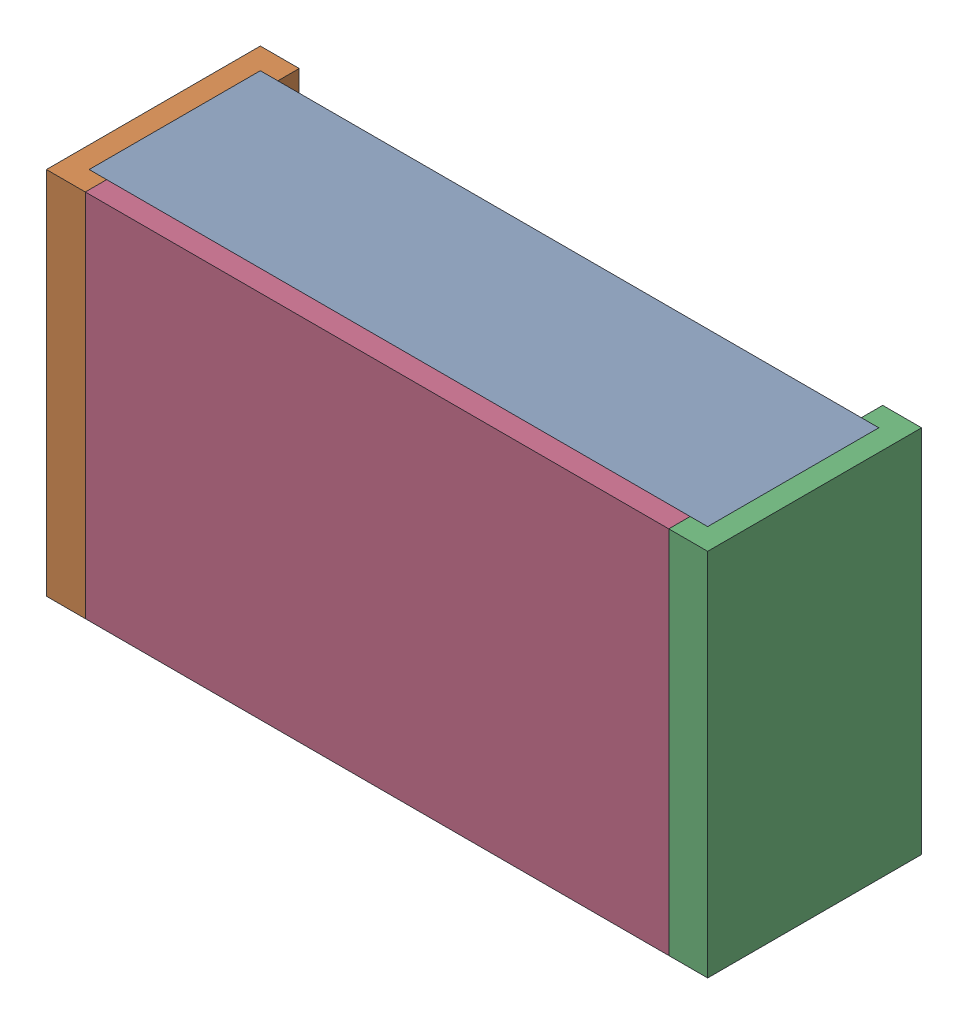
SolidWorks assembly 7434017360, configuration Default. Lengths in mm.
Overall size (1.7 0.95 0.55).
6 component instances, 3 part files, 0 mates.
Components (placement in the parent):
- Mid_Body-1: Mid_Body [Default] at (-0.85 -0.475 0) size (1.59 0.95 0.44)
- Terminal-1: Terminal [Default] at (-0.85 -0.475 0) size (0.1 0.95 0.55)
  - Open_CASCADE_STEP_translator_6.8_1.2.1-1: Open_CASCADE_STEP_translator_6.8_1.2.1 [Default] at origin size (0.1 0.95 0.55)
- Terminal-2: Terminal [Default] at (0.85 0.475 0) x (-1 0 0) z (0 0 1) size (0.1 0.95 0.55)
  - Open_CASCADE_STEP_translator_6.8_1.2.1-1: Open_CASCADE_STEP_translator_6.8_1.2.1 [Default] at origin size (0.1 0.95 0.55)
- Mark-1: Mark [Default] at (-0.75 -0.475 0.495) size (1.5 0.95 0.06)
